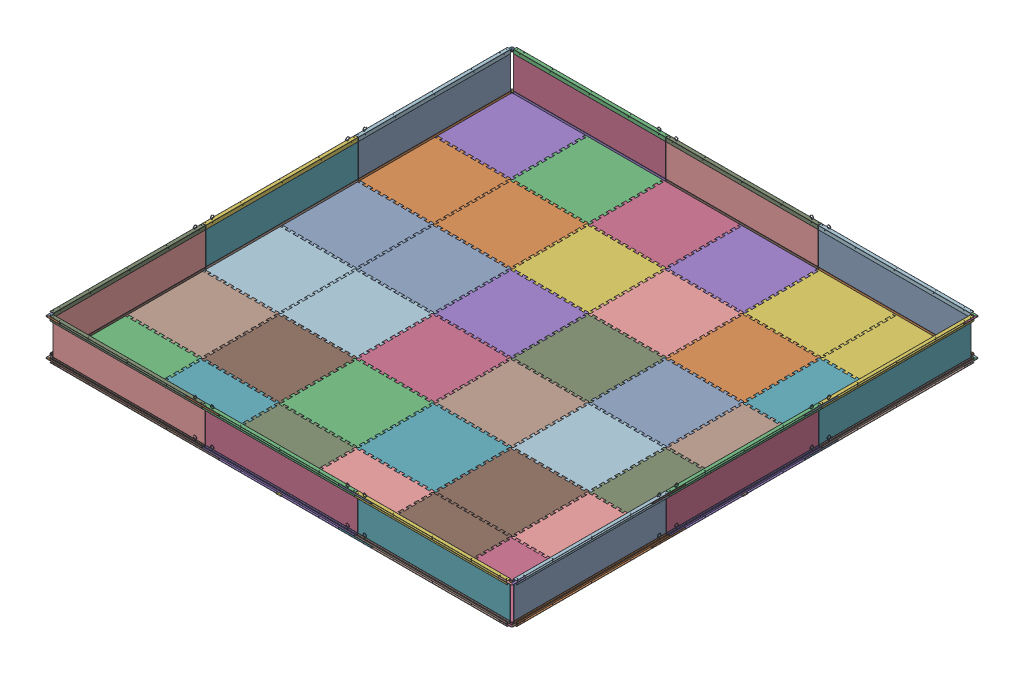
SolidWorks assembly FIELD_RelicRecovery_Perimeter and Tiles, configuration Default. Lengths in mm.
Overall size (3688.53 340.61 3688.53).
156 component instances, 11 part files, 0 mates.
Components (placement in the parent):
- FIELD_RelicRecovery_FTC Field Asm-1: FIELD_RelicRecovery_FTC Field Asm [Default] at (-2101.5112 163.7008 967.8556) x (0.999975 0 -0.007115) z (0.007115 0 0.999975) size (3662.56 340.61 3662.56)
  - FIELD_RelicRecovery_Corner Knife Hinge half-1: FIELD_RelicRecovery_Corner Knife Hinge half [Default] at (287.0747 134.4952 780.9902) x (-0.007115 0 0.999975) z (0.999975 0 0.007115) size (108.93 5.01 35.86)
  - FIELD_RelicRecovery_Corner Knife Hinge half_DefaultSM-FLAT-PATTERN-1: FIELD_RelicRecovery_Corner Knife Hinge half_DefaultSM-FLAT-PATTERN [Default] at (348.7346 132.3362 843.5339) x (-0.999975 0 -0.007115) z (0.007115 0 -0.999975) size (108.93 5.01 35.86)
  - FIELD_RelicRecovery_Corner Knife Hinge half_DefaultSM-FLAT-PATTERN-2: FIELD_RelicRecovery_Corner Knife Hinge half_DefaultSM-FLAT-PATTERN [Default] at (3867.9545 131.9552 -2749.2903) x (0.999975 0 0.007115) z (-0.007115 0 0.999975) size (108.93 5.01 35.86)
  - FIELD_RelicRecovery_Corner Knife Hinge half-2: FIELD_RelicRecovery_Corner Knife Hinge half [Default] at (3929.6145 134.1142 -2686.7466) x (0.007115 0 -0.999975) z (-0.999975 0 -0.007115) size (108.93 5.01 35.86)
  - FIELD_RelicRecovery_NewStrapClip-1: FIELD_RelicRecovery_NewStrapClip [Default] at (290.995 -150.588 -965.8349) x (-0.007115 0 0.999975) z (-0.999975 0 -0.007115) size (38.1 7.37 60.83)
  - FIELD_RelicRecovery_Rail Final Asm-1: FIELD_RelicRecovery_Rail Final Asm [Default] at (207.932 -93.3892 -853.6445) x (0.007115 0 -0.999975) z (0.999975 0 0.007115) size (1185.42 310.9 27.05)
    - FIELD_RelicRecovery_NewRail-1: FIELD_RelicRecovery_NewRail [Default] at (-479.9559 232.0754 95.5976) size (1185.42 29.72 27.05)
    - FIELD_RelicRecovery_New FTC Side Glass-1: FIELD_RelicRecovery_New FTC Side Glass [Default] at (112.7531 85.1364 102.7604) size (1185.42 270.76 3)
    - FIELD_RelicRecovery_NewRail-2: FIELD_RelicRecovery_NewRail [Default] at (705.4621 -61.8026 95.5976) x (-1 0 0) z (0 0 1) size (1185.42 29.72 27.05)
  - FIELD_RelicRecovery_Rail Final Asm-2: FIELD_RelicRecovery_Rail Final Asm [Default] at (1019.0407 -93.2622 939.0773) x (-0.999975 0 -0.007115) z (0.007115 0 -0.999975) size (1185.42 310.9 27.05)
    - FIELD_RelicRecovery_NewRail-1: FIELD_RelicRecovery_NewRail [Default] at (-479.9559 232.0754 95.5976) size (1185.42 29.72 27.05)
    - FIELD_RelicRecovery_New FTC Side Glass-1: FIELD_RelicRecovery_New FTC Side Glass [Default] at (112.7531 85.1364 102.7604) size (1185.42 270.76 3)
    - FIELD_RelicRecovery_NewRail-2: FIELD_RelicRecovery_NewRail [Default] at (705.4621 -61.8026 95.5976) x (-1 0 0) z (0 0 1) size (1185.42 29.72 27.05)
  - FIELD_RelicRecovery_Rail Final Asm-3: FIELD_RelicRecovery_Rail Final Asm [Default] at (216.3891 -93.3892 -2042.1821) x (0.007115 0 -0.999975) z (0.999975 0 0.007115) size (1185.42 310.9 27.05)
    - FIELD_RelicRecovery_NewRail-1: FIELD_RelicRecovery_NewRail [Default] at (-479.9559 232.0754 95.5976) size (1185.42 29.72 27.05)
    - FIELD_RelicRecovery_New FTC Side Glass-1: FIELD_RelicRecovery_New FTC Side Glass [Default] at (112.7531 85.1364 102.7604) size (1185.42 270.76 3)
    - FIELD_RelicRecovery_NewRail-2: FIELD_RelicRecovery_NewRail [Default] at (705.4621 -61.8026 95.5976) x (-1 0 0) z (0 0 1) size (1185.42 29.72 27.05)
  - FIELD_RelicRecovery_Rail Final Asm-4: FIELD_RelicRecovery_Rail Final Asm [Default] at (2207.5782 -93.2622 947.5344) x (-0.999975 0 -0.007115) z (0.007115 0 -0.999975) size (1185.42 310.9 27.05)
    - FIELD_RelicRecovery_NewRail-1: FIELD_RelicRecovery_NewRail [Default] at (-479.9559 232.0754 95.5976) size (1185.42 29.72 27.05)
    - FIELD_RelicRecovery_New FTC Side Glass-1: FIELD_RelicRecovery_New FTC Side Glass [Default] at (112.7531 85.1364 102.7604) size (1185.42 270.76 3)
    - FIELD_RelicRecovery_NewRail-2: FIELD_RelicRecovery_NewRail [Default] at (705.4621 -61.8026 95.5976) x (-1 0 0) z (0 0 1) size (1185.42 29.72 27.05)
  - FIELD_RelicRecovery_Rail Final Asm-5: FIELD_RelicRecovery_Rail Final Asm [Default] at (3396.1157 -93.2622 955.9914) x (-0.999975 0 -0.007115) z (0.007115 0 -0.999975) size (1185.42 310.9 27.05)
    - FIELD_RelicRecovery_NewRail-1: FIELD_RelicRecovery_NewRail [Default] at (-479.9559 232.0754 95.5976) size (1185.42 29.72 27.05)
    - FIELD_RelicRecovery_New FTC Side Glass-1: FIELD_RelicRecovery_New FTC Side Glass [Default] at (112.7531 85.1364 102.7604) size (1185.42 270.76 3)
    - FIELD_RelicRecovery_NewRail-2: FIELD_RelicRecovery_NewRail [Default] at (705.4621 -61.8026 95.5976) x (-1 0 0) z (0 0 1) size (1185.42 29.72 27.05)
  - FIELD_RelicRecovery_Rail Final Asm-6: FIELD_RelicRecovery_Rail Final Asm [Default] at (199.475 -93.3892 334.893) x (0.007115 0 -0.999975) z (0.999975 0 0.007115) size (1185.42 310.9 27.05)
    - FIELD_RelicRecovery_NewRail-1: FIELD_RelicRecovery_NewRail [Default] at (-479.9559 232.0754 95.5976) size (1185.42 29.72 27.05)
    - FIELD_RelicRecovery_New FTC Side Glass-1: FIELD_RelicRecovery_New FTC Side Glass [Default] at (112.7531 85.1364 102.7604) size (1185.42 270.76 3)
    - FIELD_RelicRecovery_NewRail-2: FIELD_RelicRecovery_NewRail [Default] at (705.4621 -61.8026 95.5976) x (-1 0 0) z (0 0 1) size (1185.42 29.72 27.05)
  - FIELD_RelicRecovery_Rail Final Asm-7: FIELD_RelicRecovery_Rail Final Asm [Default] at (4000.3001 -93.2622 136.4257) x (-0.007115 0 0.999975) z (-0.999975 0 -0.007115) size (1185.42 310.9 27.05)
    - FIELD_RelicRecovery_NewRail-1: FIELD_RelicRecovery_NewRail [Default] at (-479.9559 232.0754 95.5976) size (1185.42 29.72 27.05)
    - FIELD_RelicRecovery_New FTC Side Glass-1: FIELD_RelicRecovery_New FTC Side Glass [Default] at (112.7531 85.1364 102.7604) size (1185.42 270.76 3)
    - FIELD_RelicRecovery_NewRail-2: FIELD_RelicRecovery_NewRail [Default] at (705.4621 -61.8026 95.5976) x (-1 0 0) z (0 0 1) size (1185.42 29.72 27.05)
  - FIELD_RelicRecovery_Rail Final Asm-8: FIELD_RelicRecovery_Rail Final Asm [Default] at (4008.7571 -93.5162 -1052.1118) x (-0.007115 0 0.999975) z (-0.999975 0 -0.007115) size (1185.42 310.9 27.05)
    - FIELD_RelicRecovery_NewRail-1: FIELD_RelicRecovery_NewRail [Default] at (-479.9559 232.0754 95.5976) size (1185.42 29.72 27.05)
    - FIELD_RelicRecovery_New FTC Side Glass-1: FIELD_RelicRecovery_New FTC Side Glass [Default] at (112.7531 85.1364 102.7604) size (1185.42 270.76 3)
    - FIELD_RelicRecovery_NewRail-2: FIELD_RelicRecovery_NewRail [Default] at (705.4621 -61.8026 95.5976) x (-1 0 0) z (0 0 1) size (1185.42 29.72 27.05)
  - FIELD_RelicRecovery_Rail Final Asm-9: FIELD_RelicRecovery_Rail Final Asm [Default] at (4017.2141 -93.7702 -2240.6493) x (-0.007115 0 0.999975) z (-0.999975 0 -0.007115) size (1185.42 310.9 27.05)
    - FIELD_RelicRecovery_NewRail-1: FIELD_RelicRecovery_NewRail [Default] at (-479.9559 232.0754 95.5976) size (1185.42 29.72 27.05)
    - FIELD_RelicRecovery_New FTC Side Glass-1: FIELD_RelicRecovery_New FTC Side Glass [Default] at (112.7531 85.1364 102.7604) size (1185.42 270.76 3)
    - FIELD_RelicRecovery_NewRail-2: FIELD_RelicRecovery_NewRail [Default] at (705.4621 -61.8026 95.5976) x (-1 0 0) z (0 0 1) size (1185.42 29.72 27.05)
  - FIELD_RelicRecovery_Rail Final Asm-10: FIELD_RelicRecovery_Rail Final Asm [Default] at (2009.1109 -93.3892 -2853.2907) x (0.999975 0 0.007115) z (-0.007115 0 0.999975) size (1185.42 310.9 27.05)
    - FIELD_RelicRecovery_NewRail-1: FIELD_RelicRecovery_NewRail [Default] at (-479.9559 232.0754 95.5976) size (1185.42 29.72 27.05)
    - FIELD_RelicRecovery_New FTC Side Glass-1: FIELD_RelicRecovery_New FTC Side Glass [Default] at (112.7531 85.1364 102.7604) size (1185.42 270.76 3)
    - FIELD_RelicRecovery_NewRail-2: FIELD_RelicRecovery_NewRail [Default] at (705.4621 -61.8026 95.5976) x (-1 0 0) z (0 0 1) size (1185.42 29.72 27.05)
  - FIELD_RelicRecovery_Rail Final Asm-11: FIELD_RelicRecovery_Rail Final Asm [Default] at (3197.6485 -93.6432 -2844.8337) x (0.999975 0 0.007115) z (-0.007115 0 0.999975) size (1185.42 310.9 27.05)
    - FIELD_RelicRecovery_NewRail-1: FIELD_RelicRecovery_NewRail [Default] at (-479.9559 232.0754 95.5976) size (1185.42 29.72 27.05)
    - FIELD_RelicRecovery_New FTC Side Glass-1: FIELD_RelicRecovery_New FTC Side Glass [Default] at (112.7531 85.1364 102.7604) size (1185.42 270.76 3)
    - FIELD_RelicRecovery_NewRail-2: FIELD_RelicRecovery_NewRail [Default] at (705.4621 -61.8026 95.5976) x (-1 0 0) z (0 0 1) size (1185.42 29.72 27.05)
  - FIELD_RelicRecovery_Rail Final Asm-12: FIELD_RelicRecovery_Rail Final Asm [Default] at (820.5734 -93.3892 -2861.7477) x (0.999975 0 0.007115) z (-0.007115 0 0.999975) size (1185.42 310.9 27.05)
    - FIELD_RelicRecovery_NewRail-1: FIELD_RelicRecovery_NewRail [Default] at (-479.9559 232.0754 95.5976) size (1185.42 29.72 27.05)
    - FIELD_RelicRecovery_New FTC Side Glass-1: FIELD_RelicRecovery_New FTC Side Glass [Default] at (112.7531 85.1364 102.7604) size (1185.42 270.76 3)
    - FIELD_RelicRecovery_NewRail-2: FIELD_RelicRecovery_NewRail [Default] at (705.4621 -61.8026 95.5976) x (-1 0 0) z (0 0 1) size (1185.42 29.72 27.05)
  - FIELD_RelicRecovery_NewStrapClip-2: FIELD_RelicRecovery_NewStrapClip [Default] at (2095.4386 -150.461 864.4718) x (0.999975 0 0.007115) z (-0.007115 0 0.999975) size (38.1 7.37 60.83)
  - FIELD_RelicRecovery_NewStrapClip-3: FIELD_RelicRecovery_NewStrapClip [Default] at (2121.3013 -150.588 -2770.2278) x (-0.999975 0 -0.007115) z (0.007115 0 -0.999975) size (38.1 7.37 60.83)
  - FIELD_RelicRecovery_NewStrapClip-4: FIELD_RelicRecovery_NewStrapClip [Default] at (3925.6945 -150.715 -939.9722) x (0.007115 0 -0.999975) z (0.999975 0 0.007115) size (38.1 7.37 60.83)
  - FIELD_RelicRecovery_Corner Knife Hinge half-3: FIELD_RelicRecovery_Corner Knife Hinge half [Default] at (311.9325 -151.0008 -2712.4881) x (0.007115 0 -0.999975) z (0.999975 0 0.007115) size (108.93 5.01 35.86)
  - FIELD_RelicRecovery_Corner Knife Hinge half-4: FIELD_RelicRecovery_Corner Knife Hinge half [Default] at (3842.213 134.6222 868.3917) x (0.999975 0 0.007115) z (0.007115 0 -0.999975) size (108.93 5.01 35.86)
  - FIELD_RelicRecovery_Corner Knife Hinge half-5: FIELD_RelicRecovery_Corner Knife Hinge half [Default] at (3904.7567 -150.7468 806.7318) x (-0.007115 0 0.999975) z (-0.999975 0 -0.007115) size (108.93 5.01 35.86)
  - FIELD_RelicRecovery_Corner Knife Hinge half-6: FIELD_RelicRecovery_Corner Knife Hinge half [Default] at (3867.9545 -151.2548 -2749.2903) x (0.999975 0 0.007115) z (-0.007115 0 0.999975) size (108.93 5.01 35.86)
  - FIELD_RelicRecovery_Corner Knife Hinge half-7: FIELD_RelicRecovery_Corner Knife Hinge half [Default] at (374.4762 134.3682 -2774.1481) x (-0.999975 0 -0.007115) z (-0.007115 0 0.999975) size (108.93 5.01 35.86)
  - FIELD_RelicRecovery_Corner Knife Hinge half-8: FIELD_RelicRecovery_Corner Knife Hinge half [Default] at (348.7346 -150.8738 843.5339) x (-0.999975 0 -0.007115) z (0.007115 0 -0.999975) size (108.93 5.01 35.86)
  - FIELD_RelicRecovery_Corner Knife Hinge half_DefaultSM-FLAT-PATTERN-3: FIELD_RelicRecovery_Corner Knife Hinge half_DefaultSM-FLAT-PATTERN [Default] at (3929.6145 -149.0958 -2686.7466) x (0.007115 0 -0.999975) z (-0.999975 0 -0.007115) size (108.93 5.01 35.86)
  - FIELD_RelicRecovery_Corner Knife Hinge half_DefaultSM-FLAT-PATTERN-4: FIELD_RelicRecovery_Corner Knife Hinge half_DefaultSM-FLAT-PATTERN [Default] at (3842.213 -148.5878 868.3917) x (0.999975 0 0.007115) z (0.007115 0 -0.999975) size (108.93 5.01 35.86)
  - FIELD_RelicRecovery_Corner Knife Hinge half_DefaultSM-FLAT-PATTERN-5: FIELD_RelicRecovery_Corner Knife Hinge half_DefaultSM-FLAT-PATTERN [Default] at (3904.7567 132.3362 806.7318) x (-0.007115 0 0.999975) z (-0.999975 0 -0.007115) size (108.93 5.01 35.86)
  - FIELD_RelicRecovery_Corner Knife Hinge half_DefaultSM-FLAT-PATTERN-6: FIELD_RelicRecovery_Corner Knife Hinge half_DefaultSM-FLAT-PATTERN [Default] at (374.4762 -148.8418 -2774.1481) x (-0.999975 0 -0.007115) z (-0.007115 0 0.999975) size (108.93 5.01 35.86)
  - FIELD_RelicRecovery_Corner Knife Hinge half_DefaultSM-FLAT-PATTERN-7: FIELD_RelicRecovery_Corner Knife Hinge half_DefaultSM-FLAT-PATTERN [Default] at (311.9325 132.2092 -2712.4881) x (0.007115 0 -0.999975) z (0.999975 0 0.007115) size (108.93 5.01 35.86)
  - FIELD_RelicRecovery_Corner Knife Hinge half_DefaultSM-FLAT-PATTERN-8: FIELD_RelicRecovery_Corner Knife Hinge half_DefaultSM-FLAT-PATTERN [Default] at (287.0747 -148.7148 780.9902) x (-0.007115 0 0.999975) z (0.999975 0 0.007115) size (108.93 5.01 35.86)
  - FIELD_RelicRecovery_Strap-1: FIELD_RelicRecovery_Strap [Default] at (2083.1795 -162.1133 802.4705) x (0.007115 0 -0.999975) z (0.999975 0 0.007115) size (3547.87 7.54 25.4)
  - FIELD_RelicRecovery_Strap-2: FIELD_RelicRecovery_Strap [Default] at (352.9963 -162.2403 -978.0941) x (0.999975 0 0.007115) z (-0.007115 0 0.999975) size (3547.87 7.54 25.4)
  - FIELD_RelicRecovery_SAPA IAH-821-1: FIELD_RelicRecovery_SAPA IAH-821 [Default] at (3913.8607 138.6862 -472.7354) x (0.999975 0 0.007115) z (-0.007115 0 0.999975) size (19.05 12.7 254)
  - FIELD_RelicRecovery_SAPA IAH-821-2: FIELD_RelicRecovery_SAPA IAH-821 [Default] at (3922.3177 138.4322 -1661.2729) x (0.999975 0 0.007115) z (-0.007115 0 0.999975) size (19.05 12.7 254)
  - FIELD_RelicRecovery_SAPA IAH-821-3: FIELD_RelicRecovery_SAPA IAH-821 [Default] at (2816.7393 138.6862 861.095) x (0.007115 0 -0.999975) z (-0.999975 0 -0.007115) size (19.05 12.7 254)
  - FIELD_RelicRecovery_SAPA IAH-821-4: FIELD_RelicRecovery_SAPA IAH-821 [Default] at (1374.2082 138.6862 850.8307) x (0.007115 0 -0.999975) z (0.999975 0 0.007115) size (19.05 12.7 254)
  - FIELD_RelicRecovery_SAPA IAH-821-5: FIELD_RelicRecovery_SAPA IAH-821 [Default] at (296.1787 138.8132 -498.477) x (0.999975 0 0.007115) z (-0.007115 0 0.999975) size (19.05 12.7 254)
  - FIELD_RelicRecovery_SAPA IAH-821-6: FIELD_RelicRecovery_SAPA IAH-821 [Default] at (304.6357 138.5592 -1687.0145) x (0.999975 0 0.007115) z (-0.007115 0 0.999975) size (19.05 12.7 254)
  - FIELD_RelicRecovery_SAPA IAH-821-7: FIELD_RelicRecovery_SAPA IAH-821 [Default] at (1399.9498 138.8132 -2766.8513) x (0.007115 0 -0.999975) z (0.999975 0 0.007115) size (19.05 12.7 254)
  - FIELD_RelicRecovery_SAPA IAH-821-8: FIELD_RelicRecovery_SAPA IAH-821 [Default] at (2842.4809 138.5592 -2756.587) x (-0.007115 0 0.999975) z (-0.999975 0 -0.007115) size (19.05 12.7 254)
  - FIELD_RelicRecovery_SAPA IAH-821-9: FIELD_RelicRecovery_SAPA IAH-821 [Default] at (2816.7393 -155.4458 861.095) x (0.007115 0 -0.999975) z (-0.999975 0 -0.007115) size (19.05 12.7 254)
  - FIELD_RelicRecovery_SAPA IAH-821-10: FIELD_RelicRecovery_SAPA IAH-821 [Default] at (1374.2082 -155.4458 850.8307) x (0.007115 0 -0.999975) z (0.999975 0 0.007115) size (19.05 12.7 254)
  - FIELD_RelicRecovery_SAPA IAH-821-11: FIELD_RelicRecovery_SAPA IAH-821 [Default] at (296.1787 -155.3188 -498.477) x (0.999975 0 0.007115) z (-0.007115 0 0.999975) size (19.05 12.7 254)
  - FIELD_RelicRecovery_SAPA IAH-821-12: FIELD_RelicRecovery_SAPA IAH-821 [Default] at (304.6357 -155.5728 -1687.0145) x (0.999975 0 0.007115) z (-0.007115 0 0.999975) size (19.05 12.7 254)
  - FIELD_RelicRecovery_SAPA IAH-821-13: FIELD_RelicRecovery_SAPA IAH-821 [Default] at (1399.9498 -155.3188 -2766.8513) x (0.007115 0 -0.999975) z (0.999975 0 0.007115) size (19.05 12.7 254)
  - FIELD_RelicRecovery_SAPA IAH-821-14: FIELD_RelicRecovery_SAPA IAH-821 [Default] at (2842.4809 -155.5728 -2756.587) x (-0.007115 0 0.999975) z (-0.999975 0 -0.007115) size (19.05 12.7 254)
  - FIELD_RelicRecovery_SAPA IAH-821-15: FIELD_RelicRecovery_SAPA IAH-821 [Default] at (3922.3177 -155.6998 -1661.2729) x (0.999975 0 0.007115) z (-0.007115 0 0.999975) size (19.05 12.7 254)
  - FIELD_RelicRecovery_SAPA IAH-821-16: FIELD_RelicRecovery_SAPA IAH-821 [Default] at (3913.8607 -155.4458 -472.7354) x (0.999975 0 0.007115) z (-0.007115 0 0.999975) size (19.05 12.7 254)
  - FIELD_RelicRecovery_98404A013_98404A013-1: FIELD_RelicRecovery_98404A013_98404A013 [Default] at (2648.6838 130.4496 -2757.966) x (0 1 0) z (0 0 1) size (65.09 26.92 4.76)
  - FIELD_RelicRecovery_98404A013_98404A013-2: FIELD_RelicRecovery_98404A013_98404A013 [Default] at (2782.2844 -142.5299 -2757.0153) x (0 1 0) z (0 0 1) size (65.09 26.92 4.76)
  - FIELD_RelicRecovery_98404A013_98404A013-3: FIELD_RelicRecovery_98404A013_98404A013 [Default] at (2648.6838 -142.2759 -2757.966) x (0 1 0) z (0 0 1) size (65.09 26.92 4.76)
  - FIELD_RelicRecovery_98404A013_98404A013-4: FIELD_RelicRecovery_98404A013_98404A013 [Default] at (2782.2844 130.1956 -2757.0153) x (0 1 0) z (0 0 1) size (65.09 26.92 4.76)
  - FIELD_RelicRecovery_98404A013_98404A013-5: FIELD_RelicRecovery_98404A013_98404A013 [Default] at (1593.7469 -142.2759 -2765.4724) x (0 1 0) z (0 0 1) size (65.09 26.92 4.76)
  - FIELD_RelicRecovery_98404A013_98404A013-6: FIELD_RelicRecovery_98404A013_98404A013 [Default] at (1460.1463 128.9256 -2766.423) x (0 1 0) z (0 0 1) size (65.09 26.92 4.76)
  - FIELD_RelicRecovery_98404A013_98404A013-7: FIELD_RelicRecovery_98404A013_98404A013 [Default] at (1460.1463 -142.2759 -2766.423) x (0 1 0) z (0 0 1) size (65.09 26.92 4.76)
  - FIELD_RelicRecovery_98404A013_98404A013-8: FIELD_RelicRecovery_98404A013_98404A013 [Default] at (1593.7469 130.4496 -2765.4724) x (0 1 0) z (0 0 1) size (65.09 26.92 4.76)
  - FIELD_RelicRecovery_98404A013_98404A013-9: FIELD_RelicRecovery_98404A013_98404A013 [Default] at (303.2568 130.4496 -1493.2174) x (0 1 0) z (1 0 0) size (65.09 26.92 4.76)
  - FIELD_RelicRecovery_98404A013_98404A013-10: FIELD_RelicRecovery_98404A013_98404A013 [Default] at (1568.0053 130.4496 852.2096) x (0 1 0) z (0 0 -1) size (65.09 26.92 4.76)
  - FIELD_RelicRecovery_98404A013_98404A013-11: FIELD_RelicRecovery_98404A013_98404A013 [Default] at (3913.4324 130.4496 -412.5389) x (0 1 0) z (-1 0 0) size (65.09 26.92 4.76)
  - FIELD_RelicRecovery_98404A013_98404A013-12: FIELD_RelicRecovery_98404A013_98404A013 [Default] at (304.2074 -142.5299 -1626.818) x (0 1 0) z (1 0 0) size (65.09 26.92 4.76)
  - FIELD_RelicRecovery_98404A013_98404A013-13: FIELD_RelicRecovery_98404A013_98404A013 [Default] at (1434.4047 -142.5299 851.259) x (0 1 0) z (0 0 -1) size (65.09 26.92 4.76)
  - FIELD_RelicRecovery_98404A013_98404A013-14: FIELD_RelicRecovery_98404A013_98404A013 [Default] at (3912.4817 -142.5299 -278.9383) x (0 1 0) z (-1 0 0) size (65.09 26.92 4.76)
  - FIELD_RelicRecovery_98404A013_98404A013-15: FIELD_RelicRecovery_98404A013_98404A013 [Default] at (303.2568 -142.2759 -1493.2174) x (0 1 0) z (1 0 0) size (65.09 26.92 4.76)
  - FIELD_RelicRecovery_98404A013_98404A013-16: FIELD_RelicRecovery_98404A013_98404A013 [Default] at (1568.0053 -142.2759 852.2096) x (0 1 0) z (0 0 -1) size (65.09 26.92 4.76)
  - FIELD_RelicRecovery_98404A013_98404A013-17: FIELD_RelicRecovery_98404A013_98404A013 [Default] at (3913.4324 -142.2759 -412.5389) x (0 1 0) z (-1 0 0) size (65.09 26.92 4.76)
  - FIELD_RelicRecovery_98404A013_98404A013-18: FIELD_RelicRecovery_98404A013_98404A013 [Default] at (304.2074 130.1956 -1626.818) x (0 1 0) z (1 0 0) size (65.09 26.92 4.76)
  - FIELD_RelicRecovery_98404A013_98404A013-19: FIELD_RelicRecovery_98404A013_98404A013 [Default] at (1434.4047 130.1956 851.259) x (0 1 0) z (0 0 -1) size (65.09 26.92 4.76)
  - FIELD_RelicRecovery_98404A013_98404A013-20: FIELD_RelicRecovery_98404A013_98404A013 [Default] at (3912.4817 130.1956 -278.9383) x (0 1 0) z (-1 0 0) size (65.09 26.92 4.76)
  - FIELD_RelicRecovery_98404A013_98404A013-21: FIELD_RelicRecovery_98404A013_98404A013 [Default] at (294.7997 128.9256 -304.6799) x (0 1 0) z (1 0 0) size (65.09 26.92 4.76)
  - FIELD_RelicRecovery_98404A013_98404A013-22: FIELD_RelicRecovery_98404A013_98404A013 [Default] at (2756.5428 128.9256 860.6667) x (0 1 0) z (0 0 -1) size (65.09 26.92 4.76)
  - FIELD_RelicRecovery_98404A013_98404A013-23: FIELD_RelicRecovery_98404A013_98404A013 [Default] at (3921.8894 128.9256 -1601.0764) x (0 1 0) z (-1 0 0) size (65.09 26.92 4.76)
  - FIELD_RelicRecovery_98404A013_98404A013-24: FIELD_RelicRecovery_98404A013_98404A013 [Default] at (295.7504 -142.2759 -438.2805) x (0 1 0) z (1 0 0) size (65.09 26.92 4.76)
  - FIELD_RelicRecovery_98404A013_98404A013-25: FIELD_RelicRecovery_98404A013_98404A013 [Default] at (2622.9422 -142.2759 859.716) x (0 1 0) z (0 0 -1) size (65.09 26.92 4.76)
  - FIELD_RelicRecovery_98404A013_98404A013-26: FIELD_RelicRecovery_98404A013_98404A013 [Default] at (3920.9388 -142.2759 -1467.4758) x (0 1 0) z (-1 0 0) size (65.09 26.92 4.76)
  - FIELD_RelicRecovery_98404A013_98404A013-27: FIELD_RelicRecovery_98404A013_98404A013 [Default] at (294.7997 -142.2759 -304.6799) x (0 1 0) z (1 0 0) size (65.09 26.92 4.76)
  - FIELD_RelicRecovery_98404A013_98404A013-28: FIELD_RelicRecovery_98404A013_98404A013 [Default] at (2756.5428 -142.2759 860.6667) x (0 1 0) z (0 0 -1) size (65.09 26.92 4.76)
  - FIELD_RelicRecovery_98404A013_98404A013-29: FIELD_RelicRecovery_98404A013_98404A013 [Default] at (3921.8894 -142.2759 -1601.0764) x (0 1 0) z (-1 0 0) size (65.09 26.92 4.76)
  - FIELD_RelicRecovery_98404A013_98404A013-30: FIELD_RelicRecovery_98404A013_98404A013 [Default] at (295.7504 130.4496 -438.2805) x (0 1 0) z (1 0 0) size (65.09 26.92 4.76)
  - FIELD_RelicRecovery_98404A013_98404A013-31: FIELD_RelicRecovery_98404A013_98404A013 [Default] at (2622.9422 130.4496 859.716) x (0 1 0) z (0 0 -1) size (65.09 26.92 4.76)
  - FIELD_RelicRecovery_98404A013_98404A013-32: FIELD_RelicRecovery_98404A013_98404A013 [Default] at (3920.9388 130.4496 -1467.4758) x (0 1 0) z (-1 0 0) size (65.09 26.92 4.76)
- FIELD_RelicRecovery_Tile Field-1: FIELD_RelicRecovery_Tile Field [Default] at (-1798.9732 12.7 1804.7071) size (3603.71 12.7 3603.65)
  - FIELD_RelicRecovery_Corner soft tile-1: FIELD_RelicRecovery_Corner soft tile [Default] at (291.8914 -12.7 -291.8914) size (602.83 12.7 602.83)
  - FIELD_RelicRecovery_Corner soft tile-2: FIELD_RelicRecovery_Corner soft tile [Default] at (3306.0551 -12.7 -297.6546) x (0 0 -1) z (1 0 0) size (602.83 12.7 602.83)
  - FIELD_RelicRecovery_Corner soft tile-3: FIELD_RelicRecovery_Corner soft tile [Default] at (286.1281 -12.7 -3306.0551) x (0 0 1) z (-1 0 0) size (602.83 12.7 602.83)
  - FIELD_RelicRecovery_Corner soft tile-4: FIELD_RelicRecovery_Corner soft tile [Default] at (3300.2918 -12.7 -3311.7596) x (-1 0 0) z (0 0 -1) size (602.83 12.7 602.83)
  - FIELD_RelicRecovery_Side soft tile-1: FIELD_RelicRecovery_Side soft tile [Default] at (894.7241 -12.7 -293.0469) size (621.88 12.7 602.83)
  - FIELD_RelicRecovery_Side soft tile-2: FIELD_RelicRecovery_Side soft tile [Default] at (290.7358 -12.7 -894.7241) x (0 0 1) z (-1 0 0) size (621.88 12.7 602.83)
  - FIELD_RelicRecovery_Side soft tile-3: FIELD_RelicRecovery_Side soft tile [Default] at (1497.5568 -12.7 -294.2025) size (621.88 12.7 602.83)
  - FIELD_RelicRecovery_Side soft tile-4: FIELD_RelicRecovery_Side soft tile [Default] at (2100.3896 -12.7 -295.3581) size (621.88 12.7 602.83)
  - FIELD_RelicRecovery_Side soft tile-5: FIELD_RelicRecovery_Side soft tile [Default] at (2703.2223 -12.7 -296.5137) size (621.88 12.7 602.83)
  - FIELD_RelicRecovery_Side soft tile-6: FIELD_RelicRecovery_Side soft tile [Default] at (289.5802 -12.7 -1497.5568) x (0 0 1) z (-1 0 0) size (621.88 12.7 602.83)
  - FIELD_RelicRecovery_Side soft tile-7: FIELD_RelicRecovery_Side soft tile [Default] at (288.4246 -12.7 -2100.3896) x (0 0 1) z (-1 0 0) size (621.88 12.7 602.83)
  - FIELD_RelicRecovery_Side soft tile-8: FIELD_RelicRecovery_Side soft tile [Default] at (287.2691 -12.7 -2703.2223) x (0 0 1) z (-1 0 0) size (621.88 12.7 602.83)
  - FIELD_RelicRecovery_Side soft tile-9: FIELD_RelicRecovery_Side soft tile [Default] at (888.9609 -12.7 -3307.196) x (-1 0 0) z (0 0 -1) size (621.88 12.7 602.83)
  - FIELD_RelicRecovery_Side soft tile-10: FIELD_RelicRecovery_Side soft tile [Default] at (1491.7936 -12.7 -3308.3369) x (-1 0 0) z (0 0 -1) size (621.88 12.7 602.83)
  - FIELD_RelicRecovery_Side soft tile-11: FIELD_RelicRecovery_Side soft tile [Default] at (2094.6264 -12.7 -3309.4778) x (-1 0 0) z (0 0 -1) size (621.88 12.7 602.83)
  - FIELD_RelicRecovery_Side soft tile-12: FIELD_RelicRecovery_Side soft tile [Default] at (2697.4591 -12.7 -3310.6187) x (-1 0 0) z (0 0 -1) size (621.88 12.7 602.83)
  - FIELD_RelicRecovery_Side soft tile-13: FIELD_RelicRecovery_Side soft tile [Default] at (3301.4327 -12.7 -2708.9269) x (0 0 -1) z (1 0 0) size (621.88 12.7 602.83)
  - FIELD_RelicRecovery_Side soft tile-14: FIELD_RelicRecovery_Side soft tile [Default] at (3302.5737 -12.7 -2106.0942) x (0 0 -1) z (1 0 0) size (621.88 12.7 602.83)
  - FIELD_RelicRecovery_Side soft tile-15: FIELD_RelicRecovery_Side soft tile [Default] at (3303.7146 -12.7 -1503.2614) x (0 0 -1) z (1 0 0) size (621.88 12.7 602.83)
  - FIELD_RelicRecovery_Side soft tile-16: FIELD_RelicRecovery_Side soft tile [Default] at (3304.8555 -12.7 -900.4287) x (0 0 -1) z (1 0 0) size (621.88 12.7 602.83)
  - FIELD_RelicRecovery_Standard soft tile-1: FIELD_RelicRecovery_Standard soft tile [Default] at (893.5685 -12.7 -895.8797) size (621.88 12.7 621.88)
  - FIELD_RelicRecovery_Standard soft tile-2: FIELD_RelicRecovery_Standard soft tile [Default] at (892.413 -12.7 -1498.7124) size (621.88 12.7 621.88)
  - FIELD_RelicRecovery_Standard soft tile-3: FIELD_RelicRecovery_Standard soft tile [Default] at (891.2574 -12.7 -2101.5452) size (621.88 12.7 621.88)
  - FIELD_RelicRecovery_Standard soft tile-4: FIELD_RelicRecovery_Standard soft tile [Default] at (890.1018 -12.7 -2704.3779) size (621.88 12.7 621.88)
  - FIELD_RelicRecovery_Standard soft tile-5: FIELD_RelicRecovery_Standard soft tile [Default] at (1496.4013 -12.7 -897.0353) size (621.88 12.7 621.88)
  - FIELD_RelicRecovery_Standard soft tile-6: FIELD_RelicRecovery_Standard soft tile [Default] at (1495.2457 -12.7 -1499.868) size (621.88 12.7 621.88)
  - FIELD_RelicRecovery_Standard soft tile-7: FIELD_RelicRecovery_Standard soft tile [Default] at (1494.0901 -12.7 -2102.7007) size (621.88 12.7 621.88)
  - FIELD_RelicRecovery_Standard soft tile-8: FIELD_RelicRecovery_Standard soft tile [Default] at (1492.9345 -12.7 -2705.5335) size (621.88 12.7 621.88)
  - FIELD_RelicRecovery_Standard soft tile-9: FIELD_RelicRecovery_Standard soft tile [Default] at (2099.234 -12.7 -898.1908) size (621.88 12.7 621.88)
  - FIELD_RelicRecovery_Standard soft tile-10: FIELD_RelicRecovery_Standard soft tile [Default] at (2098.0784 -12.7 -1501.0236) size (621.88 12.7 621.88)
  - FIELD_RelicRecovery_Standard soft tile-11: FIELD_RelicRecovery_Standard soft tile [Default] at (2096.9228 -12.7 -2103.8563) size (621.88 12.7 621.88)
  - FIELD_RelicRecovery_Standard soft tile-12: FIELD_RelicRecovery_Standard soft tile [Default] at (2095.7673 -12.7 -2706.689) size (621.88 12.7 621.88)
  - FIELD_RelicRecovery_Standard soft tile-13: FIELD_RelicRecovery_Standard soft tile [Default] at (2702.0667 -12.7 -899.3464) size (621.88 12.7 621.88)
  - FIELD_RelicRecovery_Standard soft tile-14: FIELD_RelicRecovery_Standard soft tile [Default] at (2700.9112 -12.7 -1502.1791) size (621.88 12.7 621.88)
  - FIELD_RelicRecovery_Standard soft tile-15: FIELD_RelicRecovery_Standard soft tile [Default] at (2699.7556 -12.7 -2105.0119) size (621.88 12.7 621.88)
  - FIELD_RelicRecovery_Standard soft tile-16: FIELD_RelicRecovery_Standard soft tile [Default] at (2698.6 -12.7 -2707.8446) size (621.88 12.7 621.88)
